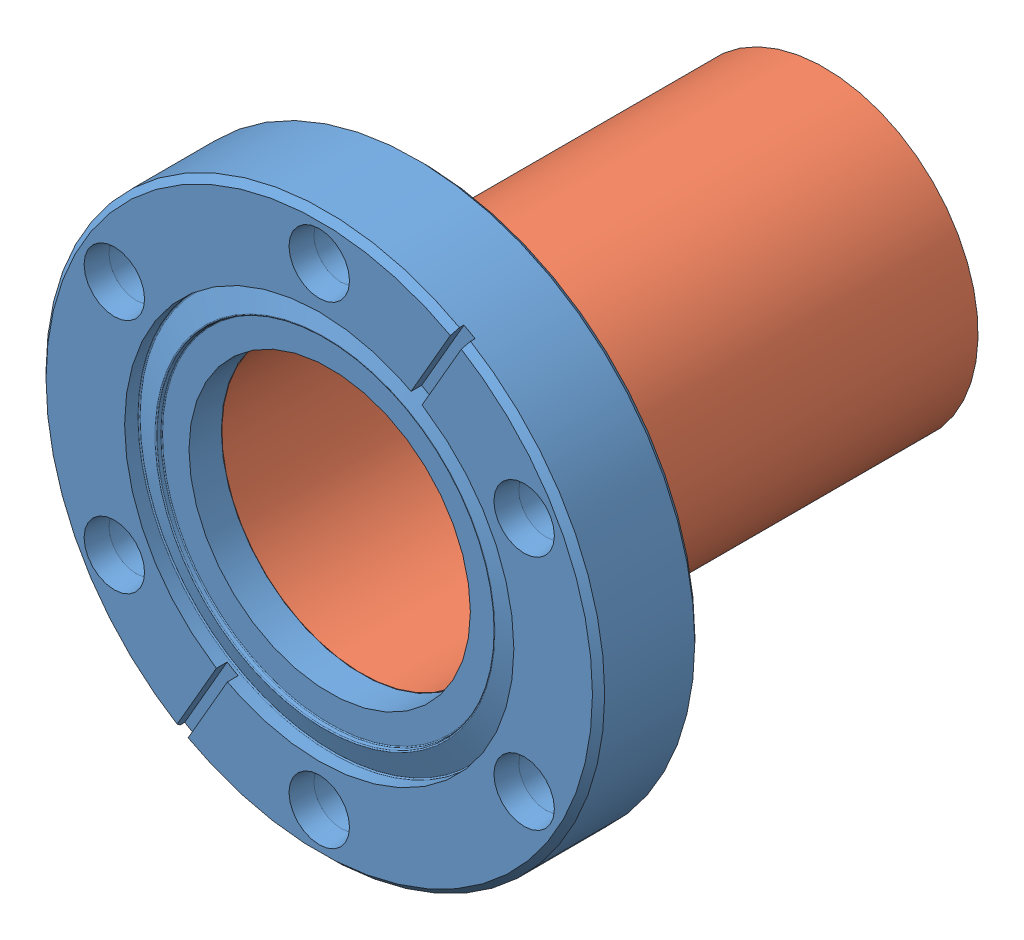
SolidWorks assembly 401002, configuration Default. Lengths in mm.
Overall size (69.34 69.34 62.71).
2 component instances, 2 part files, 2 mates.
Components (placement in the parent):
- 110014-REV.A-1: 110014-REV.A [Default] at (23.3262 39.7424 45.8095) size (69.34 69.34 12.7)
- 940102-1: 940102 [Default] at (23.3262 39.7424 -4.2031) x (0.999529 -0.030697 0) z (0 0 1) size (38.1 38.1 57.4)
Mates (geometry in assembly coordinates):
- Concentric1: concentric: cylinder of 110014-REV.A-1 through (23.3262 39.7424 45.8095) axis (0 0 -1) radius 19.177; cylinder of 940102-1 through (23.3262 39.7424 53.2009) axis (0 0 -1) radius 19.05
- Coincident1: coincident anti-aligned: plane of 110014-REV.A-1 through (42.5032 39.7424 53.2009) normal (0 0 -1); plane of 940102-1 through (23.3262 39.7424 53.2009) normal (0 0 1)
